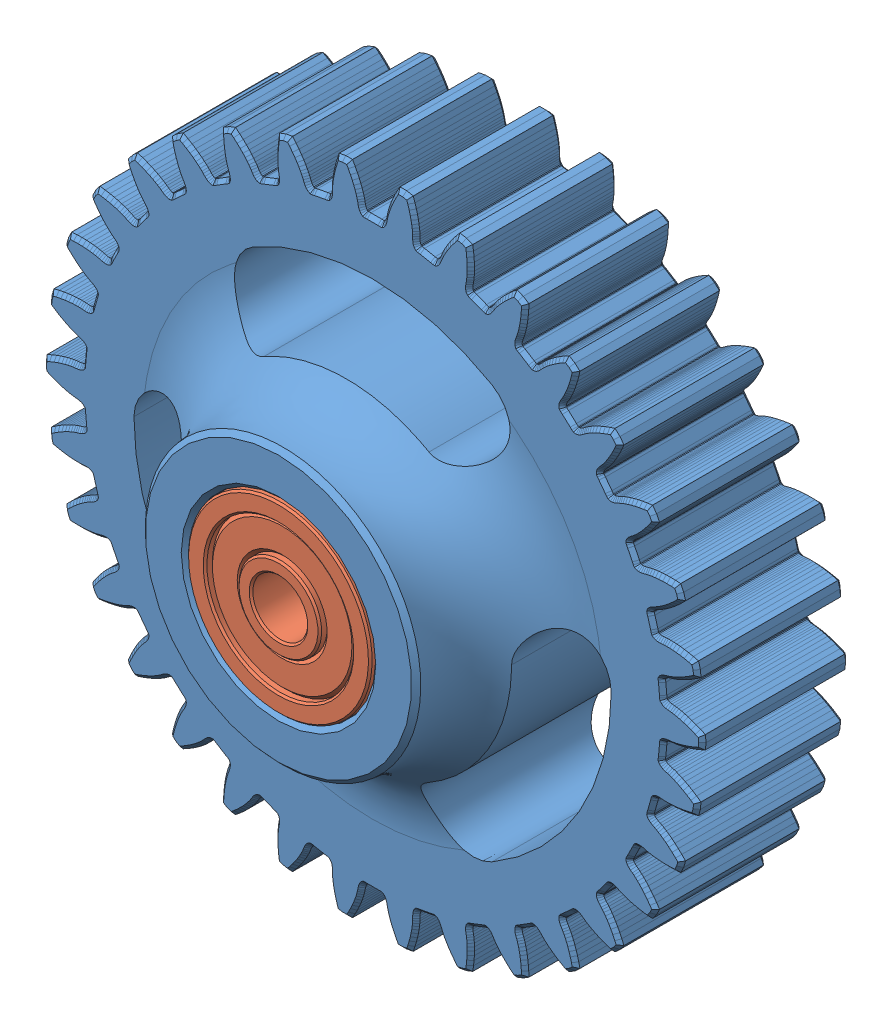
SolidWorks assembly transmission_planet_gear_with_bearings, configuration Default. Lengths in mm.
Overall size (35.93 35.78 18.25).
3 component instances, 2 part files, 4 mates.
Components (placement in the parent):
- transmission_planet_gear-1: transmission_planet_gear [Default] at origin size (35.93 35.78 18.25)
- 623zz-1: 623zz [Default] at (0 0 7.125) x (0.499247 0.866459 0) z (-0.866459 0.499247 0) size (10 4 10)
- 623zz-2: 623zz [Default] at (0 0 -7.125) x (1 0 0) z (0 1 0) size (10 4 10)
Mates (geometry in assembly coordinates):
- Concentric1: concentric anti-aligned: circle of transmission_planet_gear-1; circle of 623zz-1
- Coincident1: coincident anti-aligned: plane of transmission_planet_gear-1 through (0 0 5.125) normal (0 0 1); plane of 623zz-1 through (0 0 5.125) normal (0 0 -1)
- Coincident2: coincident anti-aligned: plane of transmission_planet_gear-1 through (0 0 -5.125) normal (0 0 -1); plane of 623zz-2 through (0 0 -5.125) normal (0 0 1)
- Concentric2: concentric aligned: cylinder of transmission_planet_gear-1 through (0 0 -5.125) axis (0 0 -1) radius 5.05; cylinder of 623zz-2 through (0 0 -9.125) axis (0 0 -1) radius 5
